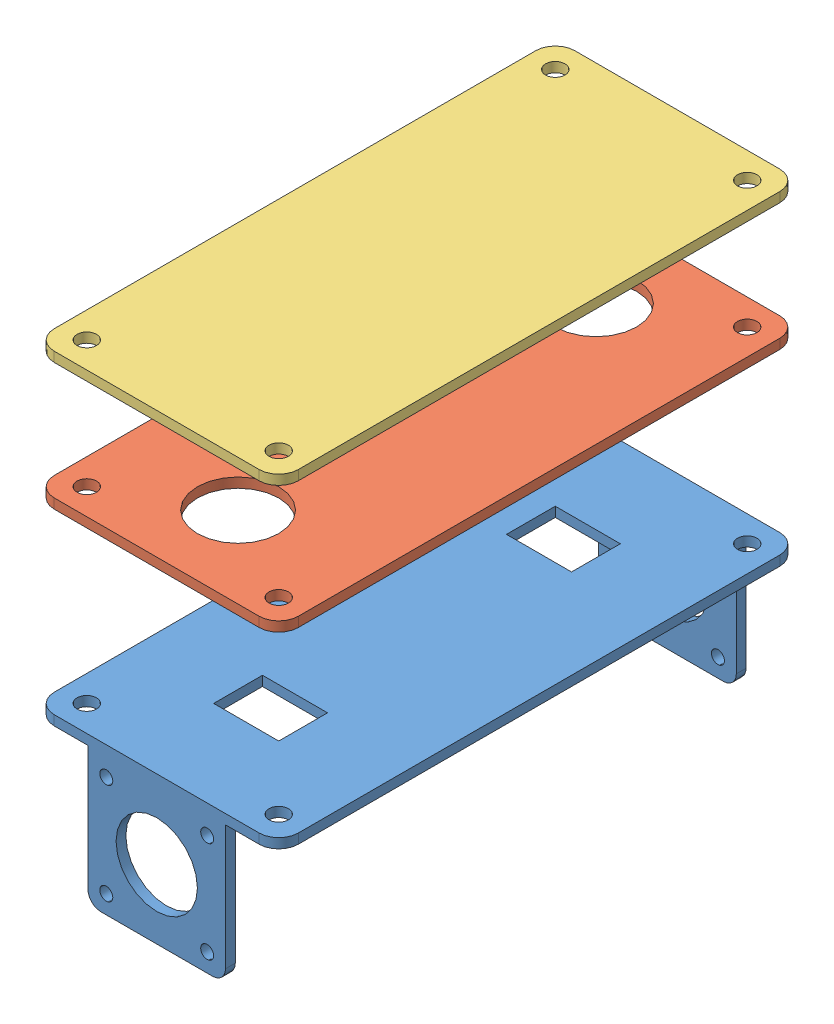
SolidWorks assembly Ensamblaje1, configuration Predeterminado. Lengths in mm.
Overall size (75 142.06 160).
3 component instances, 3 part files, 4 mates.
Components (placement in the parent):
- Base inferior-1: Base inferior [Predeterminado] at (-9.1542 -8.8844 237) size (75 45.3 160)
- Base intermedia-1: Base intermedia [Predeterminado] at (-9.1542 72.9655 160) x (-1 0 0) z (0 -1 0) size (75 160 3)
- Base superior-1: Base superior [Predeterminado] at (-9.1542 112.0251 160) x (1 0 0) z (0 -1 0) size (75 160 3)
Mates (geometry in assembly coordinates):
- Concéntrica3: concentric aligned: cylinder of Base inferior-1 through (20.3458 15.2656 232) axis (0 -1 0) radius 3; circle of Base intermedia-1
- Concéntrica4: concentric aligned: cylinder of Base inferior-1 through (20.3458 15.2656 88) axis (0 -1 0) radius 3; circle of Base intermedia-1
- Concéntrica5: concentric aligned: circle of Base intermedia-1; circle of Base superior-1
- Concéntrica6: concentric aligned: circle of Base intermedia-1; circle of Base superior-1
